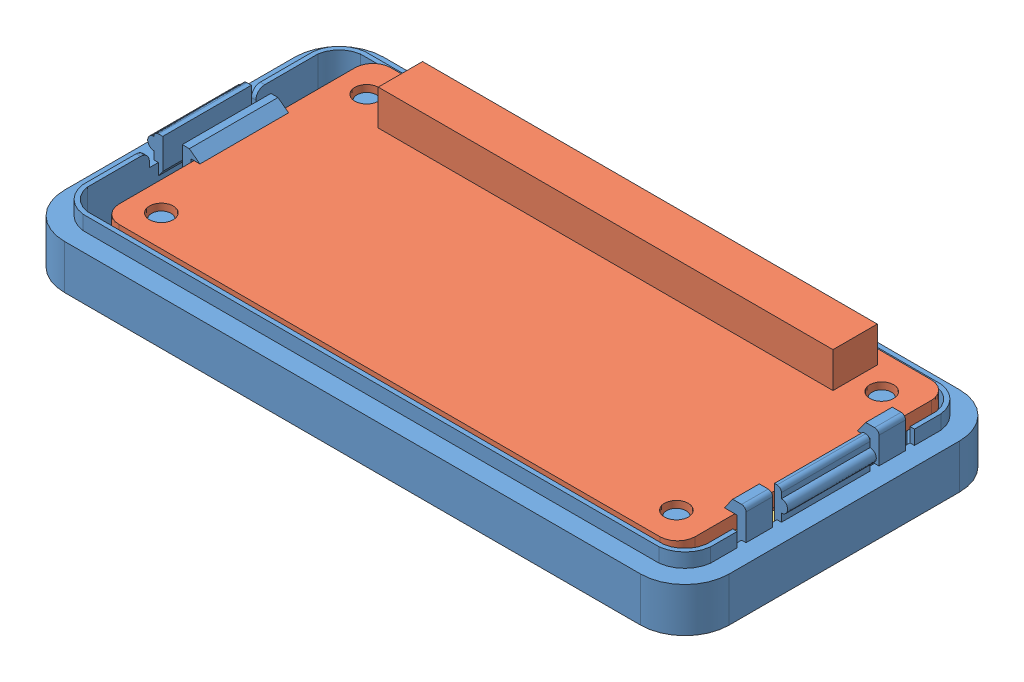
SolidWorks assembly jot_bonnet_comp, configuration 默认. Lengths in mm.
Overall size (75 17.04 36).
3 component instances, 3 part files, 1 mates.
Components (placement in the parent):
- pisugar_case_joy_bonnet_cap-1: pisugar_case_joy_bonnet_cap [默认] at (20.2735 -71.165 -12.2647) size (75 8.5 36)
- jot_bonnet-1: jot_bonnet [默认] at (23.0661 -64.065 -14.9846) x (1 0 0) z (0 0 -1) size (65 17.04 30.64)
- pisugar_case_joy_bonnet_buttons-1: pisugar_case_joy_bonnet_buttons [默认] at (46.637 -69.3123 -6.8457) size (43.22 5.29 24.11)
Mates (geometry in assembly coordinates):
- 重合1: coincident: plane of assembly; plane of assembly; plane of pisugar_case_joy_bonnet_cap-1 through (-8.9802 -65.665 -0.4172) normal (0 1 0); plane of jot_bonnet-1 through (23.0661 -65.665 -14.9846) normal (0 -1 0)
